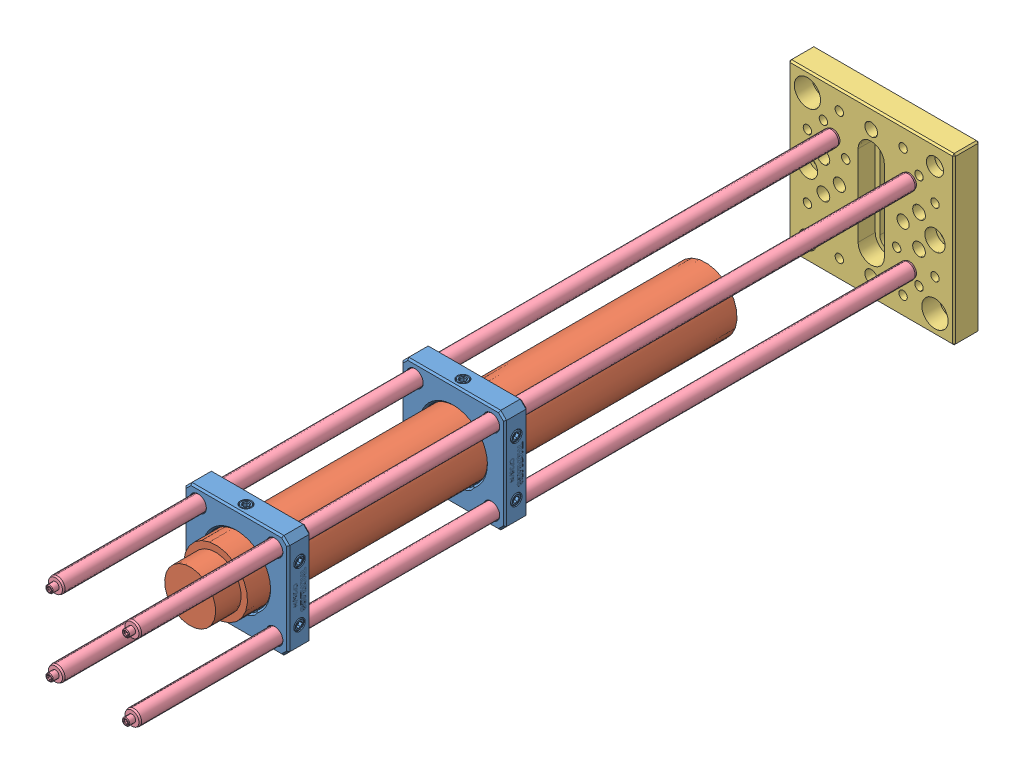
SolidWorks assembly Mag03Mount1V0, configuration Default. Lengths in mm.
Overall size (65 65 317.34).
8 component instances, 4 part files, 14 mates.
Components (placement in the parent):
- CP35_M-Step_Mag03Holder-1: CP35_M-Step_Mag03Holder [Default] at (-19.9986 3.5176 62.0754) size (40.87 40.64 8.89)
- CP35_M-Step_Mag03Holder-2: CP35_M-Step_Mag03Holder [Default] at (-19.9986 3.5176 -22.9246) size (40.87 40.64 8.89)
- Mag03_Bartington-1: Mag03_Bartington [Default] at (-19.9986 3.5176 74.6304) x (0.187811 -0.982205 0) z (0.982205 0.187811 0) size (25 202 25)
- UBP2_M-Solidworks-1: UBP2_M-Solidworks [Default] at (-52.4987 36.0176 -182.3696) x (-1 0 0) z (0 1 0) size (65 10 65)
- ER12-Solidworks-1: ER12-Solidworks [Default] at (-4.6153 17.0149 -27.4836) x (-0.533875 -0.845563 0) z (0.845563 -0.533875 0) size (5.99 309.88 5.99)
- ER12-Solidworks-2: ER12-Solidworks [Default] at (-33.9327 -10.356 -27.4836) x (1 0 0) z (0 1 0) size (5.99 309.88 5.99)
- ER12-Solidworks-3: ER12-Solidworks [Default] at (-35.7748 19.8601 -27.4836) x (0.284808 0.958585 0) z (-0.958585 0.284808 0) size (5.99 309.88 5.99)
- ER12-Solidworks-4: ER12-Solidworks [Default] at (-5.701 -12.8651 -27.4836) x (-0.958863 -0.283868 0) z (0.283868 -0.958863 0) size (5.99 309.88 5.99)
Mates (geometry in assembly coordinates):
- Concentric1: concentric aligned: cylinder of CP35_M-Step_Mag03Holder-1 through (-19.9986 3.5176 58.9004) axis (0 0 1) radius 12.7762; cylinder of CP35_M-Step_Mag03Holder-2 through (-19.9986 3.5176 -26.0996) axis (0 0 1) radius 12.7762
- Concentric2: concentric aligned: cylinder of CP35_M-Step_Mag03Holder-1 through (-19.9986 3.5176 58.9004) axis (0 0 1) radius 12.7762; cylinder of Mag03_Bartington-1 through (-19.9986 3.5176 -32.3696) axis (0 0 1) radius 12.5
- Distance1: distance = 90 mm aligned: plane of CP35_M-Step_Mag03Holder-2 through (-40.3186 -16.8024 -27.3696) normal (0 0 -1); plane of Mag03_Bartington-1 through (-19.9986 3.5176 -117.3696) normal (0 0 -1)
- Concentric3: concentric anti-aligned: cylinder of CP35_M-Step_Mag03Holder-2 through (-4.9987 18.5175 -27.3696) axis (0 0 1) radius 3.0099; cylinder of ER12-Solidworks-1 through (-4.9987 18.5175 -182.3696) axis (0 0 -1) radius 2.9972
- Concentric4: concentric anti-aligned: cylinder of CP35_M-Step_Mag03Holder-2 through (-34.9986 18.5175 -27.3696) axis (0 0 1) radius 3.0099; cylinder of ER12-Solidworks-3 through (-34.9986 18.5175 -182.3696) axis (0 0 -1) radius 2.9972
- Concentric5: concentric anti-aligned: cylinder of CP35_M-Step_Mag03Holder-2 through (-34.9986 -11.4824 -27.3696) axis (0 0 1) radius 3.0099; cylinder of ER12-Solidworks-2 through (-34.9986 -11.4824 -182.3696) axis (0 0 -1) radius 2.9972
- Concentric6: concentric anti-aligned: cylinder of CP35_M-Step_Mag03Holder-1 through (-4.9987 -11.4824 57.6304) axis (0 0 1) radius 3.0099; cylinder of ER12-Solidworks-4 through (-4.9987 -11.4824 -182.3696) axis (0 0 -1) radius 2.9972
- Distance2: distance = 75 mm aligned: plane of Mag03_Bartington-1 through (-19.9986 3.5176 -117.3696) normal (0 0 -1); plane of UBP2_M-Solidworks-1 through (12.5013 -28.9824 -192.3696) normal (0 0 -1)
- Concentric7: concentric anti-aligned: cylinder of CP35_M-Step_Mag03Holder-2 through (-4.9987 -11.4824 -27.3696) axis (0 0 1) radius 3.0099; cylinder of ER12-Solidworks-4 through (-4.9987 -11.4824 -182.3696) axis (0 0 -1) radius 2.9972
- Distance3: distance = 85 mm aligned: plane of CP35_M-Step_Mag03Holder-2 through (-40.3186 -16.8024 -27.3696) normal (0 0 -1); plane of CP35_M-Step_Mag03Holder-1 through (-40.3186 -16.8024 57.6304) normal (0 0 -1)
- Coincident10: coincident anti-aligned: plane of UBP2_M-Solidworks-1 through (12.5013 -28.9824 -182.3696) normal (0 0 1); plane of ER12-Solidworks-4 through (-4.9987 -11.4824 -182.3696) normal (0 0 -1)
- Coincident11: coincident anti-aligned: plane of UBP2_M-Solidworks-1 through (12.5013 -28.9824 -182.3696) normal (0 0 1); plane of ER12-Solidworks-1 through (-4.9987 18.5175 -182.3696) normal (0 0 -1)
- Coincident12: coincident anti-aligned: plane of UBP2_M-Solidworks-1 through (12.5013 -28.9824 -182.3696) normal (0 0 1); plane of ER12-Solidworks-3 through (-34.9986 18.5175 -182.3696) normal (0 0 -1)
- Coincident13: coincident anti-aligned: plane of UBP2_M-Solidworks-1 through (12.5013 -28.9824 -182.3696) normal (0 0 1); plane of ER12-Solidworks-2 through (-34.9986 -11.4824 -182.3696) normal (0 0 -1)
